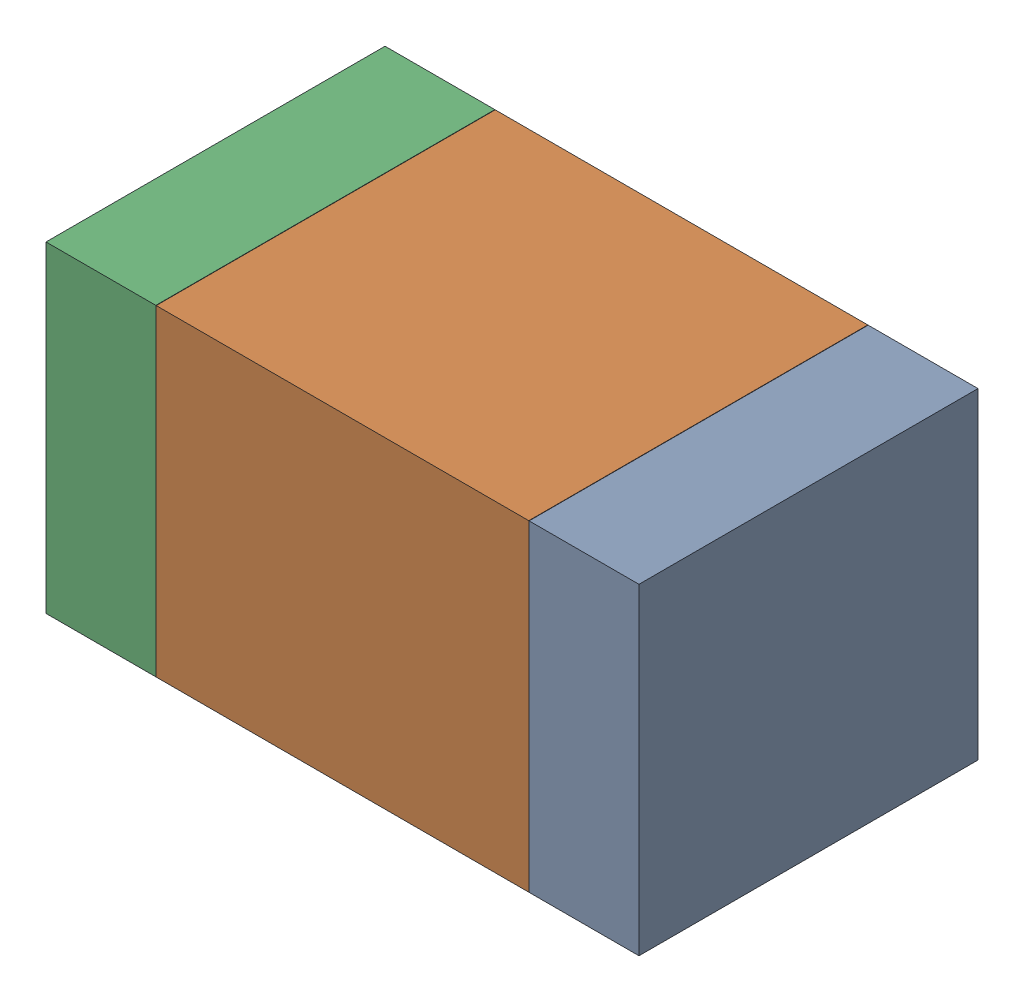
SolidWorks assembly R15, configuration Default. Lengths in mm.
Overall size (1.75 0.95 1).
6 component instances, 2 part files, 0 mates.
Components (placement in the parent):
- 6575498272-1: 6575498272 [Default] at (16.7145 16.256 0) size (0.32 0.95 1)
  - Extruded_8-1: Extruded_8 [Default] at origin size (0.32 0.95 1)
- 6575498112-1: 6575498112 [Default] at (16.002 16.256 0) size (1.1 0.95 1)
  - Extruded_9-1: Extruded_9 [Default] at origin size (1.1 0.95 1)
- 6575498272-2: 6575498272 [Default] at (15.2895 16.256 0) size (0.32 0.95 1)
  - Extruded_8-1: Extruded_8 [Default] at origin size (0.32 0.95 1)
